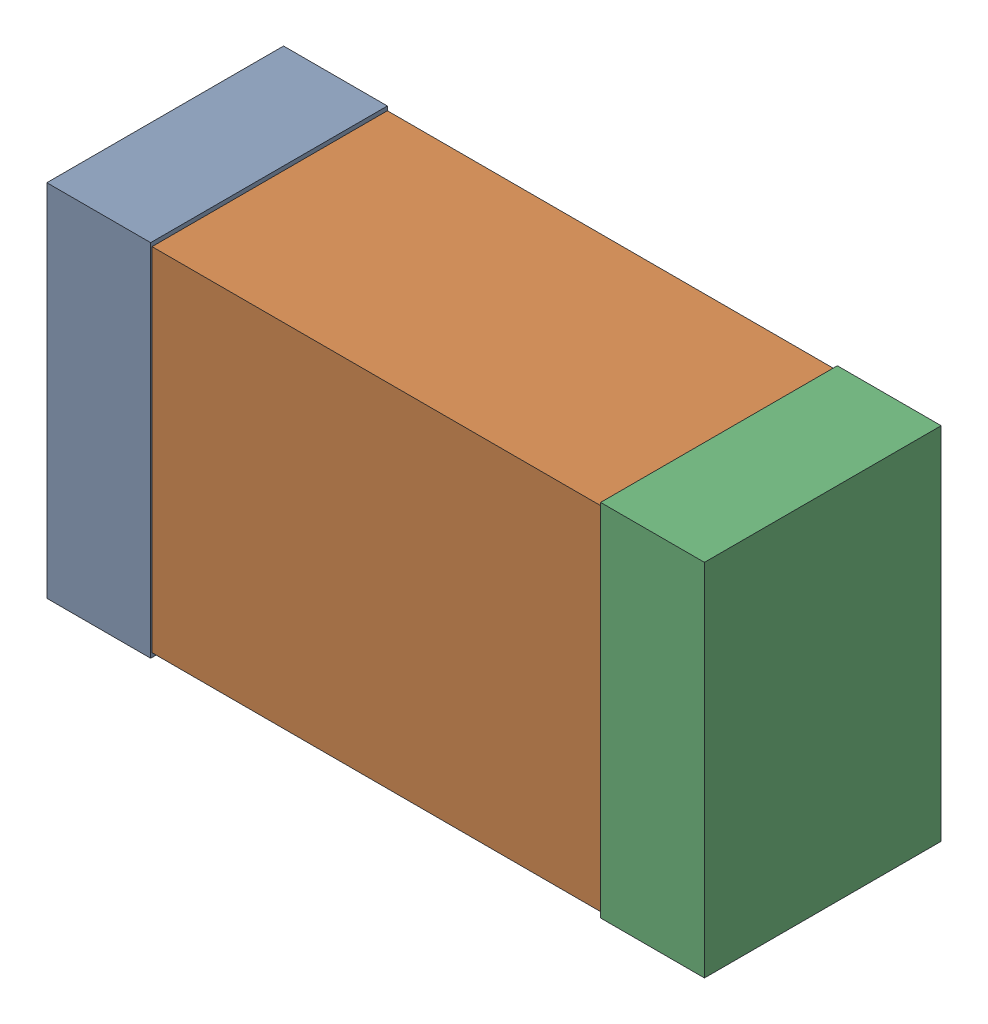
SolidWorks assembly R5Kanaloa_v2.0.0_GPIO_b, configuration Default. Lengths in mm.
Overall size (2.38 1.3 0.85).
6 component instances, 2 part files, 0 mates.
Components (placement in the parent):
- 352877648-1: 352877648 [Default] at (61.611 45.974 0) size (0.38 1.3 0.85)
  - Extruded_14-1: Extruded_14 [Default] at origin size (0.38 1.3 0.85)
- 352877904-1: 352877904 [Default] at (62.611 45.974 0) size (2.2 1.27 0.85)
  - Extruded_18-1: Extruded_18 [Default] at origin size (2.2 1.27 0.85)
- 352877648-2: 352877648 [Default] at (63.611 45.974 0) size (0.38 1.3 0.85)
  - Extruded_14-1: Extruded_14 [Default] at origin size (0.38 1.3 0.85)
